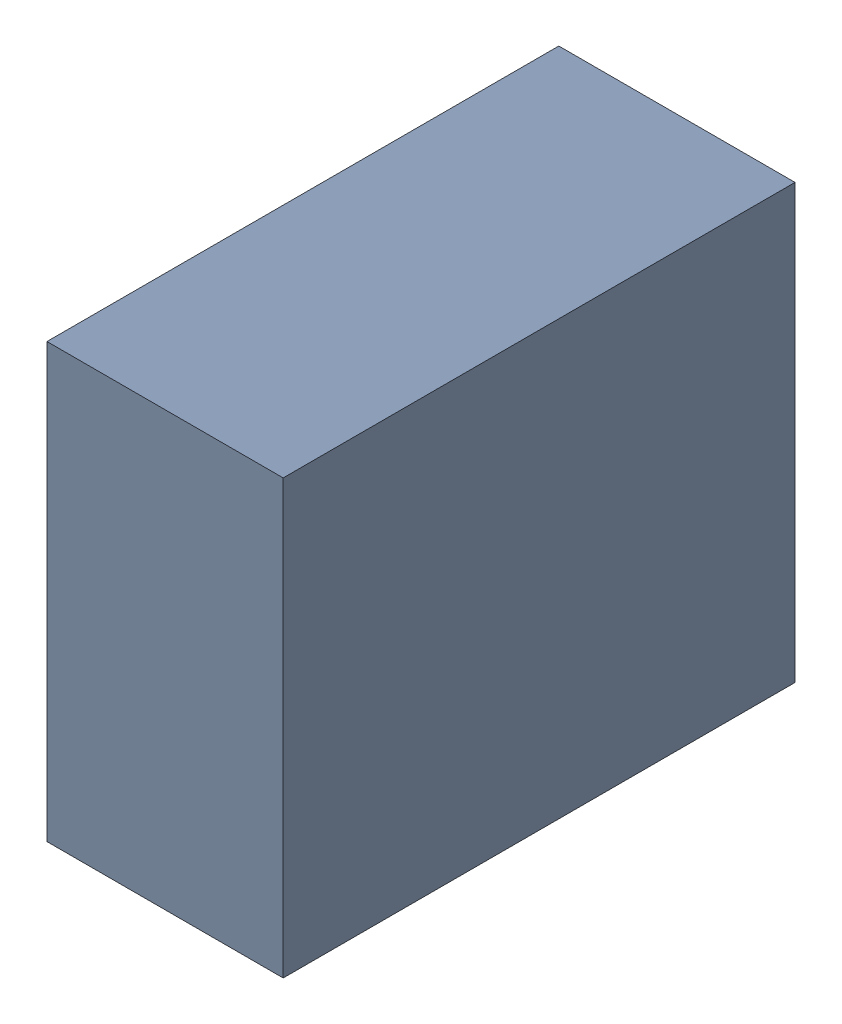
SolidWorks assembly C21_TDA4, configuration Standard. Lengths in mm.
Overall size (0.6 1.1 1.3).
2 component instances, 1 part files, 0 mates.
Components (placement in the parent):
- 885542376-1: 885542376 [Standard] at (4.88 -49.99 0) size (0.6 1.1 1.3)
  - Extruded_25-1: Extruded_25 [Standard] at origin size (0.6 1.1 1.3)
